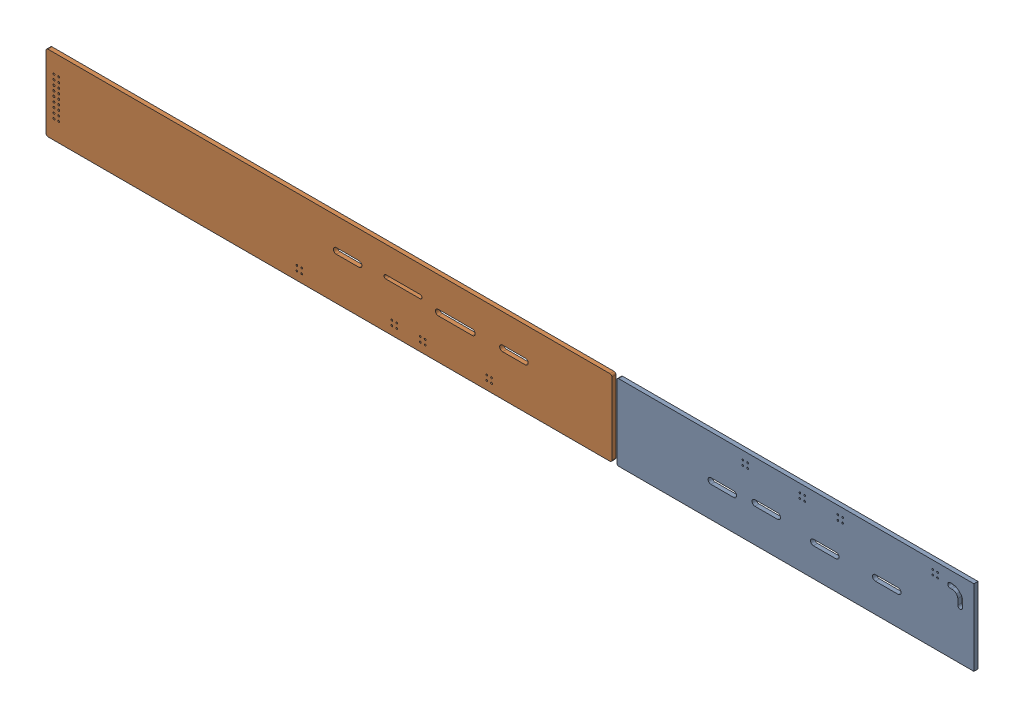
SolidWorks assembly Board-1, configuration По умолчанию. Lengths in mm.
Overall size (488.85 40 2.16).
2 component instances, 2 part files, 0 mates.
Components (placement in the parent):
- Board-Part-1-1: Board-Part-1 [По умолчанию] at (0 0 -2.1614) size (188.1 40 2.16)
- Board-Part-2-1: Board-Part-2 [По умолчанию] at (0 0 -2.1614) size (298.1 40 2.16)
